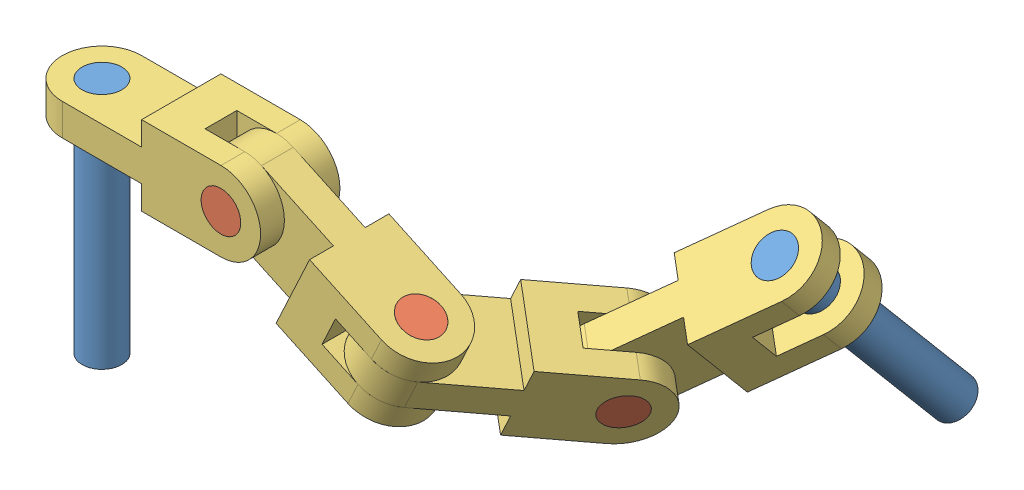
SolidWorks assembly Ej 3, configuration Predeterminado. Lengths in mm.
Overall size (743.15 346.45 523.17).
9 component instances, 3 part files, 21 mates.
Components (placement in the parent):
- Examen EJER3-1-1: Examen EJER3-1 [Default] at origin size (50 300 50)
- Examen EJER3-2-3: Examen EJER3-2 [Default] at (200 -20 50) x (0.944306 0.329069 0) z (0.329069 -0.944306 0) size (50 100 50)
- Examen EJER3-3-4: Examen EJER3-3 [Default] at (100 -20 0) x (0 -1 0) z (0 0 1) size (100 300 100)
- Examen EJER3-3-5: Examen EJER3-3 [Default] at (290.6308 -62.2618 0) x (0 0 -1) z (-0.422618 -0.906308 0) size (100 300 100)
- Examen EJER3-3-6: Examen EJER3-3 [Default] at (433.2452 -128.764 -81.9152) x (0.422618 0.906308 0) z (-0.742404 0.346189 -0.573576) size (100 300 100)
- Examen EJER3-2-4: Examen EJER3-2 [Default] at (360.1306 -149.839 0) x (-0.074928 0.03494 -0.996577) z (-0.903205 0.421171 0.082674) size (50 100 50)
- Examen EJER3-3-7: Examen EJER3-3 [Default] at (551.0178 -99.1586 -216.4845) x (-0.742404 0.346189 -0.573576) z (0.126564 -0.768256 -0.627507) size (100 300 100)
- Examen EJER3-2-5: Examen EJER3-2 [Default] at (522.3491 -170.3139 -135.1516) x (0.129522 -0.765826 -0.629869) z (-0.657313 -0.541908 0.523713) size (50 100 50)
- Examen EJER3-1-2: Examen EJER3-1 [Default] at (610.4785 -6.9001 -237.7632) x (-0.606499 -0.56051 0.563904) z (-0.784946 0.309212 -0.536887) size (50 300 50)
Mates (geometry in assembly coordinates):
- Coincidente6: coordinate: point of Examen EJER3-1-1
- Concéntrica1: concentric anti-aligned: cylinder of Examen EJER3-1-1 through (0 -300 0) axis (0 1 0) radius 25; cylinder of Examen EJER3-3-4 through (0 30 0) axis (0 -1 0) radius 25
- Coincidente19: coincident aligned: circle of Examen EJER3-1-1; circle of Examen EJER3-3-4
- Paralelo9: parallel anti-aligned: line of Examen EJER3-3-4 through (100 0 50) axis (-1 0 0)
- Coincidente29: coincident anti-aligned: plane of Examen EJER3-3-4 through (250 30 20) normal (0 0 -1); plane of Examen EJER3-3-5 through (200 -20 20) normal (0 0 1)
- Coincidente30: coincident aligned: circle of Examen EJER3-3-4; circle of Examen EJER3-3-5
- Ángulo4: planar angle = 2.70526 rad aligned: line of Examen EJER3-3-4 through (200 30 50) axis (-1 0 0); line of Examen EJER3-3-5 through (221.1309 25.3154 20) axis (0.906308 -0.422618 0)
- Concéntrica2: concentric anti-aligned: cylinder of Examen EJER3-2-3 through (200 -20 -50) axis (0 0 1) radius 25; cylinder of Examen EJER3-3-5 through (200 -20 50) axis (0 0 -1) radius 25
- Coincidente34: coincident aligned: circle of Examen EJER3-2-3; circle of Examen EJER3-3-4
- Coincidente35: coincident anti-aligned: plane of Examen EJER3-3-5 through (418.1246 -143.7807 50) normal (0.422618 0.906308 0); plane of Examen EJER3-3-6 through (372.8092 -122.6498 0) normal (-0.422618 -0.906308 0)
- Coincidente36: coincident aligned: circle of Examen EJER3-3-5; circle of Examen EJER3-3-6
- Ángulo5: planar angle = 2.181662 rad aligned: line of Examen EJER3-3-5 through (311.7617 -16.9464 -50) axis (0.906308 -0.422618 0); line of Examen EJER3-3-6 through (404.5774 -93.3285 -110.594) axis (-0.519837 0.242404 0.819152)
- Concéntrica3: concentric anti-aligned: cylinder of Examen EJER3-3-6 through (360.1306 -149.8391 0) axis (0.422618 0.906308 0) radius 25; cylinder of Examen EJER3-2-4 through (402.3925 -59.2083 0) axis (-0.422618 -0.906308 0) radius 25
- Coincidente38: coincident aligned: circle of Examen EJER3-3-5; circle of Examen EJER3-2-4
- Coincidente39: coincident anti-aligned: plane of Examen EJER3-3-6 through (475.2418 -203.5162 -216.2595) normal (0.742404 -0.346189 0.573576); plane of Examen EJER3-3-7 through (470.3808 -146.0807 -175.3019) normal (-0.742404 0.346189 -0.573576)
- Coincidente40: coincident aligned: circle of Examen EJER3-3-6; circle of Examen EJER3-3-7
- Ángulo9: planar angle = 0.872665 rad aligned: line of Examen EJER3-3-6 through (491.4963 -100.7581 -53.2364) axis (0.519837 -0.242404 -0.819152); line of Examen EJER3-3-7 through (493.7488 -121.5154 -120.9835) axis (0.657889 0.538458 -0.526541)
- Concéntrica4: concentric anti-aligned: cylinder of Examen EJER3-3-7 through (522.3491 -170.3139 -135.1516) axis (-0.742404 0.346189 -0.573576) radius 25; cylinder of Examen EJER3-2-5 through (448.1087 -135.695 -192.5092) axis (0.742404 -0.346189 0.573576) radius 25
- Coincidente47: coincident anti-aligned: circle of Examen EJER3-3-6; circle of Examen EJER3-2-5
- Concéntrica5: concentric anti-aligned: cylinder of Examen EJER3-3-7 through (610.4785 -6.9001 -237.7632) axis (0.126564 -0.768256 -0.627507) radius 25; cylinder of Examen EJER3-1-2 through (648.4478 -237.3768 -426.0153) axis (-0.126564 0.768256 0.627507) radius 25
- Coincidente48: coincident anti-aligned: circle of Examen EJER3-3-7; circle of Examen EJER3-1-2
